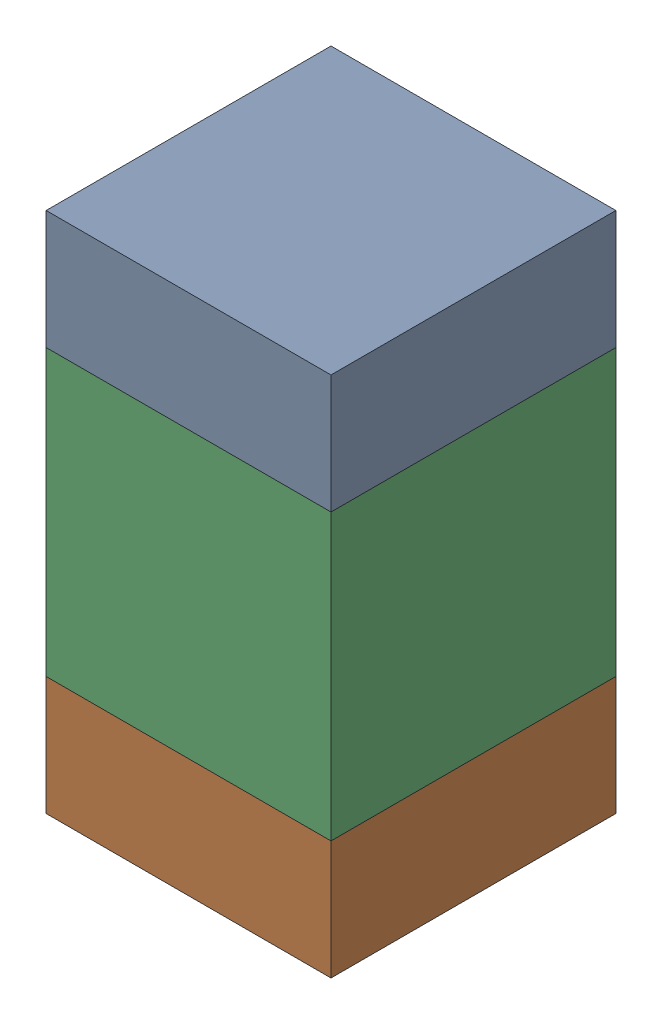
SolidWorks assembly C105_2PCB, configuration Default. Lengths in mm.
Overall size (0.6 1.1 0.6).
6 component instances, 2 part files, 0 mates.
Components (placement in the parent):
- 854785296-1: 854785296 [Default] at (107.5 85.025 0) size (0.6 0.25 0.6)
  - Extruded_10-1: Extruded_10 [Default] at origin size (0.6 0.25 0.6)
- 854785296-2: 854785296 [Default] at (107.5 84.175 0) size (0.6 0.25 0.6)
  - Extruded_10-1: Extruded_10 [Default] at origin size (0.6 0.25 0.6)
- 761606048-1: 761606048 [Default] at (107.5 84.6 0) size (0.6 0.6 0.6)
  - Extruded_9-1: Extruded_9 [Default] at origin size (0.6 0.6 0.6)
